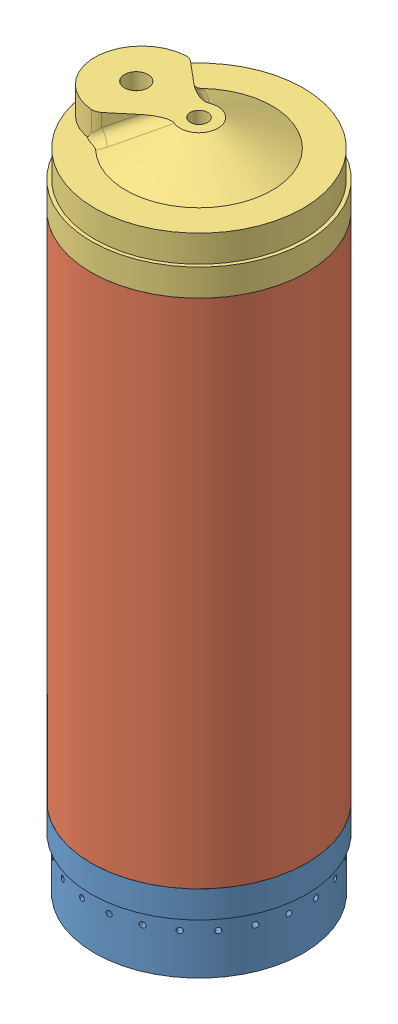
SolidWorks assembly LOXTank, configuration Default. Lengths in mm.
Overall size (255.14 663.94 255.14).
3 component instances, 3 part files, 6 mates.
Components (placement in the parent):
- IT-U-Bulkhead-1: IT-U-Bulkhead [Default] at (0 37.5444 37.5444) x (-1 0 0) z (0 0 1) size (203.2 135.82 203.2)
- LOXTankCylinder-1: LOXTankCylinder [Default] at (0 557.6887 0) x (0 -1 0) z (0.953159 0 -0.302469) size (482.6 203.2 203.2)
- UT-T-Bulkhead_V5-1: UT-T-Bulkhead_V5 [Default] at (0 595.63 -37.9413) x (-1 0 0) z (0 0 -1) size (203.2 75.88 203.2)
Mates (geometry in assembly coordinates):
- Concentric3: concentric aligned: circle of LOXTankCylinder-1; circle of UT-T-Bulkhead_V5-1
- Coincident12: coincident anti-aligned: plane of LOXTankCylinder-1 through (0 719.0284 0) normal (0 1 0); plane of UT-T-Bulkhead_V5-1 through (0 719.0284 0) normal (0 -1 0)
- Concentric4: concentric anti-aligned: circle of IT-U-Bulkhead-1; circle of LOXTankCylinder-1
- Coincident14: coincident anti-aligned: plane of IT-U-Bulkhead-1 through (0 236.4284 0) normal (0 1 0); plane of LOXTankCylinder-1 through (0 236.4284 0) normal (0 -1 0)
- Concentric5: concentric aligned: cylinder of IT-U-Bulkhead-1 through (0 75.0887 0) axis (0 1 0) radius 8.0962
- Coincident15: coincident anti-aligned: plane of IT-U-Bulkhead-1 through (0 0 0) normal (0 -1 0)
